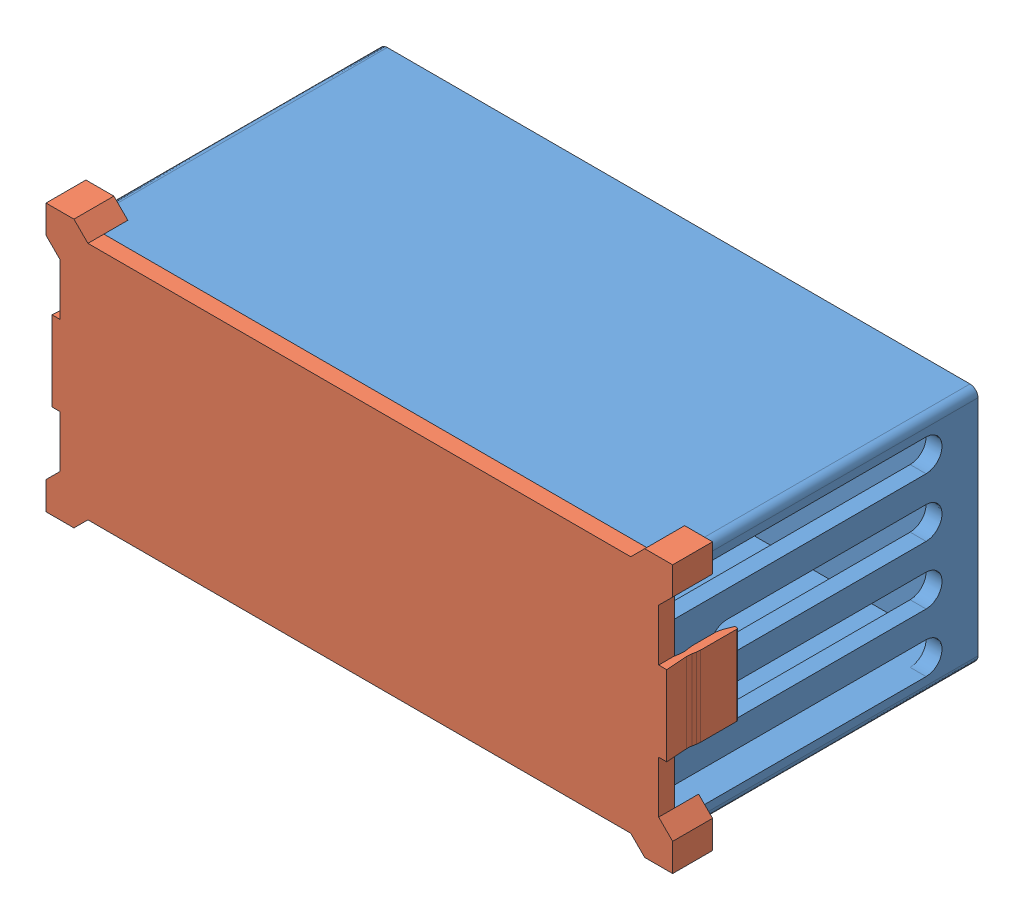
SolidWorks assembly GabbiaBatteria, configuration Type1. Lengths in mm.
Overall size (157 67 80).
2 component instances, 2 part files, 7 mates.
Components (placement in the parent):
- CaseBatteria-1: CaseBatteria [Type1] at (0 0 -38) x (1 0 0) z (0 0 -1) size (151 60 76)
- CoperchioCase-1: CoperchioCase [Type1] at origin size (157 67 17.98)
Mates (geometry in assembly coordinates):
- Coincidente6: coincident anti-aligned: plane of CaseBatteria-1 through (0 0 -38) normal (0 -1 0); plane of assembly through (0 0 0) normal (0 1 0)
- Parallelo1: parallel anti-aligned: plane of CaseBatteria-1 through (0 0 -38) normal (0 0 -1); plane of assembly through (0 0 0) normal (0 0 1)
- Coincidente10: coincident aligned: plane of CaseBatteria-1 through (-75 30 -76) normal (-1 0 0); plane of CoperchioCase-1 through (-75 -30 4) normal (-1 0 0)
- Coincidente9: coincident aligned: plane of CaseBatteria-1 through (-75 -30 -76) normal (0 -1 0); plane of CoperchioCase-1 through (75 -30 4) normal (0 -1 0)
- Coincidente11: coincident aligned: plane of CaseBatteria-1 through (-75 -30 -76) normal (0 -1 0); plane of CoperchioCase-1 through (75 -30 4) normal (0 -1 0)
- Coincidente12: coincident aligned: plane of CaseBatteria-1 through (-75 30 -76) normal (-1 0 0); plane of CoperchioCase-1 through (-75 -30 4) normal (-1 0 0)
- Coincidente13: coincident anti-aligned: plane of CaseBatteria-1 through (0 0 0) normal (0 0 1); plane of CoperchioCase-1 through (0 0 0) normal (0 0 -1)
